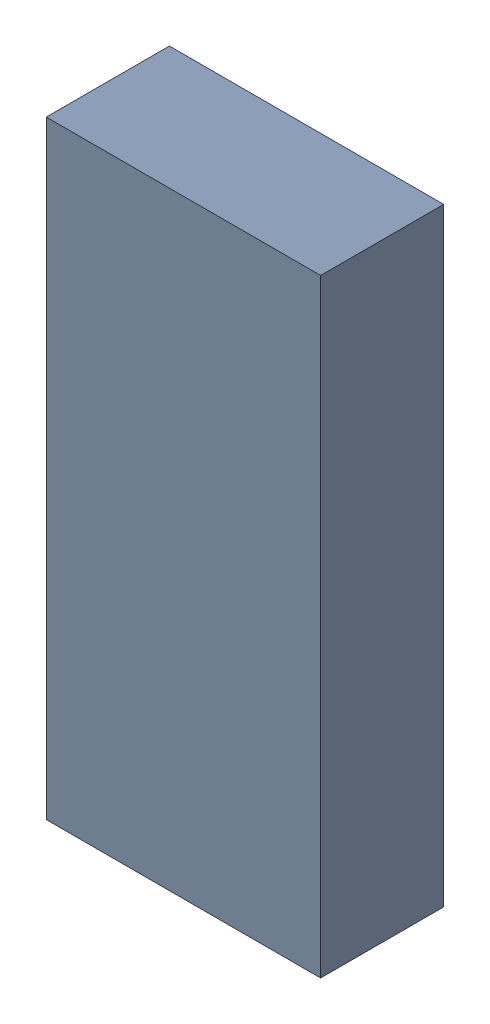
SolidWorks assembly U1, configuration Default. Lengths in mm.
Overall size (3.9 8.65 1.75).
2 component instances, 1 part files, 0 mates.
Components (placement in the parent):
- 402663056-1: 402663056 [Default] at (179.705 97.79 -2.8524) size (3.9 8.65 1.75)
  - Extruded_27-1: Extruded_27 [Default] at origin size (3.9 8.65 1.75)
